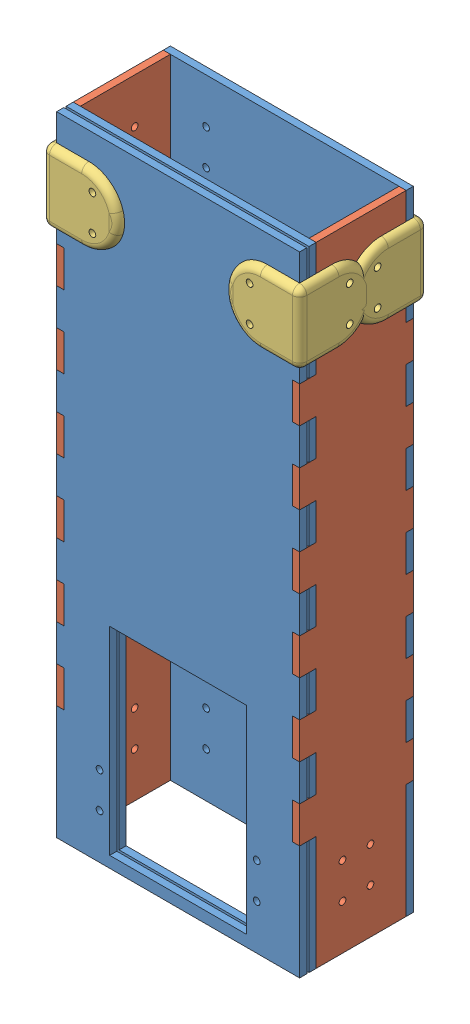
SolidWorks assembly Interaction_Box, configuration Default. Lengths in mm.
Overall size (114.3 279.4 56.88).
9 component instances, 3 part files, 28 mates.
Components (placement in the parent):
- front_back-1: front_back [Front] at (114.8789 48.9442 274.6837) size (107.95 279.4 3.17)
- side-1: side [Side] at (114.8789 48.9442 230.5087) x (0 0 1) z (-1 0 0) size (50.52 279.4 3.17)
- side-2: side [Side] at (219.6539 48.9442 230.5087) x (0 0 1) z (-1 0 0) size (50.52 279.4 3.17)
- front_back-2: front_back [Side] at (114.8789 48.9442 227.3337) size (107.95 279.4 3.17)
- wall_bracket-1: wall_bracket [double_holes] at (111.7039 316.3442 277.8587) x (0 -1 0) z (0 0 1) size (31.75 34.21 34.21)
- wall_bracket-2: wall_bracket [double_holes] at (219.6539 284.5942 277.8587) x (0 1 0) z (0 0 1) size (31.75 34.21 34.21)
- wall_bracket-3: wall_bracket [double_holes] at (219.6539 284.5942 227.3337) x (0 1 0) z (1 0 0) size (31.75 34.21 34.21)
- wall_bracket-4: wall_bracket [double_holes] at (111.7039 316.3442 227.3337) x (0 -1 0) z (-1 0 0) size (31.75 34.21 34.21)
- front_back-3: front_back [Front] at (114.8789 48.9442 270.5087) size (107.95 279.4 3.17)
Mates (geometry in assembly coordinates):
- Coincident3: coincident: plane of side-1 through (111.7039 48.9442 230.5087) normal (-1 0 0); plane of wall_bracket-1 through (111.7039 284.5942 246.1087) normal (1 0 0)
- Concentric1: concentric: cylinder of wall_bracket-1 through (115.9465 308.3442 258.8087) axis (-1 0 0) radius 1.5; cylinder of side-1 through (119.1215 308.3442 258.8087) axis (-1 0 0) radius 1.5
- Concentric2: concentric: cylinder of wall_bracket-1 through (115.9465 292.5942 258.8087) axis (-1 0 0) radius 1.5; cylinder of side-1 through (119.1215 292.5942 258.8087) axis (-1 0 0) radius 1.5
- Concentric3: concentric: cylinder of front_back-1 through (130.7539 308.3442 270.4411) axis (0 0 1) radius 1.5; cylinder of wall_bracket-1 through (130.7539 308.3432 246.1087) axis (0 0 1) radius 1.5
- Concentric6: concentric: cylinder of front_back-1 through (130.7539 292.5942 270.4411) axis (0 0 1) radius 1.5; cylinder of wall_bracket-1 through (130.7539 292.5952 246.1087) axis (0 0 1) radius 1.5
- Coincident4: coincident: plane of front_back-1 through (114.8789 48.9442 277.8587) normal (0 0 1); plane of wall_bracket-1 through (111.7039 284.5942 277.8587) normal (0 0 -1)
- Coincident5: coincident: plane of front_back-1 through (114.8789 48.9442 277.8587) normal (0 0 1); plane of wall_bracket-2 through (219.6539 316.3442 277.8587) normal (0 0 -1)
- Concentric7: concentric: cylinder of front_back-1 through (200.6039 308.3442 270.4411) axis (0 0 1) radius 1.5; cylinder of wall_bracket-2 through (200.6039 308.3432 246.1087) axis (0 0 1) radius 1.5
- Concentric8: concentric: cylinder of front_back-1 through (200.6039 292.5942 270.4411) axis (0 0 1) radius 1.5; cylinder of wall_bracket-2 through (200.6039 292.5952 246.1087) axis (0 0 1) radius 1.5
- Coincident6: coincident: plane of side-2 through (219.6539 48.9442 230.5087) normal (1 0 0); plane of wall_bracket-2 through (219.6539 316.3442 246.1087) normal (-1 0 0)
- Concentric9: concentric: cylinder of wall_bracket-2 through (215.4112 308.3442 258.8087) axis (1 0 0) radius 1.5; cylinder of side-2 through (223.8965 308.3442 258.8087) axis (-1 0 0) radius 1.5
- Concentric10: concentric: cylinder of wall_bracket-2 through (215.4112 292.5942 258.8087) axis (1 0 0) radius 1.5; cylinder of side-2 through (223.8965 292.5942 258.8087) axis (-1 0 0) radius 1.5
- Coincident7: coincident: plane of front_back-2 through (114.8789 48.9442 227.3337) normal (0 0 -1); plane of wall_bracket-3 through (187.9039 316.3442 227.3337) normal (0 0 1)
- Concentric11: concentric: cylinder of front_back-2 through (200.6039 308.3442 223.0911) axis (0 0 1) radius 1.5; cylinder of wall_bracket-3 through (200.6039 308.3442 231.5764) axis (0 0 -1) radius 1.5
- Concentric12: concentric: cylinder of front_back-2 through (200.6039 292.5942 223.0911) axis (0 0 1) radius 1.5; cylinder of wall_bracket-3 through (200.6039 292.5942 231.5764) axis (0 0 -1) radius 1.5
- Coincident8: coincident: plane of side-2 through (219.6539 48.9442 230.5087) normal (1 0 0); plane of wall_bracket-3 through (219.6539 316.3442 227.3337) normal (-1 0 0)
- Concentric13: concentric: cylinder of side-2 through (223.8965 308.3442 246.3837) axis (-1 0 0) radius 1.5; cylinder of wall_bracket-3 through (187.9039 308.3432 246.3837) axis (1 0 0) radius 1.5
- Concentric14: concentric: cylinder of side-2 through (223.8965 292.5942 246.3837) axis (-1 0 0) radius 1.5; cylinder of wall_bracket-3 through (187.9039 292.5952 246.3837) axis (1 0 0) radius 1.5
- Coincident9: coincident: plane of front_back-2 through (114.8789 48.9442 227.3337) normal (0 0 -1); plane of wall_bracket-4 through (143.4539 284.5942 227.3337) normal (0 0 1)
- Concentric15: concentric: cylinder of front_back-2 through (130.7539 308.3442 223.0911) axis (0 0 1) radius 1.5; cylinder of wall_bracket-4 through (130.7539 308.3442 231.5764) axis (0 0 -1) radius 1.5
- Concentric16: concentric: cylinder of front_back-2 through (130.7539 292.5942 223.0911) axis (0 0 1) radius 1.5; cylinder of wall_bracket-4 through (130.7539 292.5942 231.5764) axis (0 0 -1) radius 1.5
- Concentric17: concentric: cylinder of side-1 through (119.1215 308.3442 246.3837) axis (-1 0 0) radius 1.5; cylinder of wall_bracket-4 through (143.4539 308.3432 246.3837) axis (-1 0 0) radius 1.5
- Concentric18: concentric: cylinder of side-1 through (119.1215 292.5942 246.3837) axis (-1 0 0) radius 1.5; cylinder of wall_bracket-4 through (143.4539 292.5952 246.3837) axis (-1 0 0) radius 1.5
- Concentric19: concentric: cylinder of wall_bracket-1 through (130.7539 308.3432 246.1087) axis (0 0 1) radius 1.5; cylinder of front_back-3 through (130.7539 308.3442 266.2661) axis (0 0 1) radius 1.5
- Concentric20: concentric: cylinder of wall_bracket-1 through (130.7539 292.5952 246.1087) axis (0 0 1) radius 1.5; cylinder of front_back-3 through (130.7539 292.5942 266.2661) axis (0 0 1) radius 1.5
- Concentric21: concentric: cylinder of wall_bracket-2 through (200.6039 308.3432 246.1087) axis (0 0 1) radius 1.5; cylinder of front_back-3 through (200.6039 308.3442 266.2661) axis (0 0 1) radius 1.5
- Concentric22: concentric: cylinder of wall_bracket-2 through (200.6039 292.5952 246.1087) axis (0 0 1) radius 1.5; cylinder of front_back-3 through (200.6039 292.5942 266.2661) axis (0 0 1) radius 1.5
- Coincident10: coincident: plane of side-1 through (111.7039 48.9442 270.5087) normal (0 0 1); plane of front_back-3 through (114.8789 48.9442 270.5087) normal (0 0 -1)
